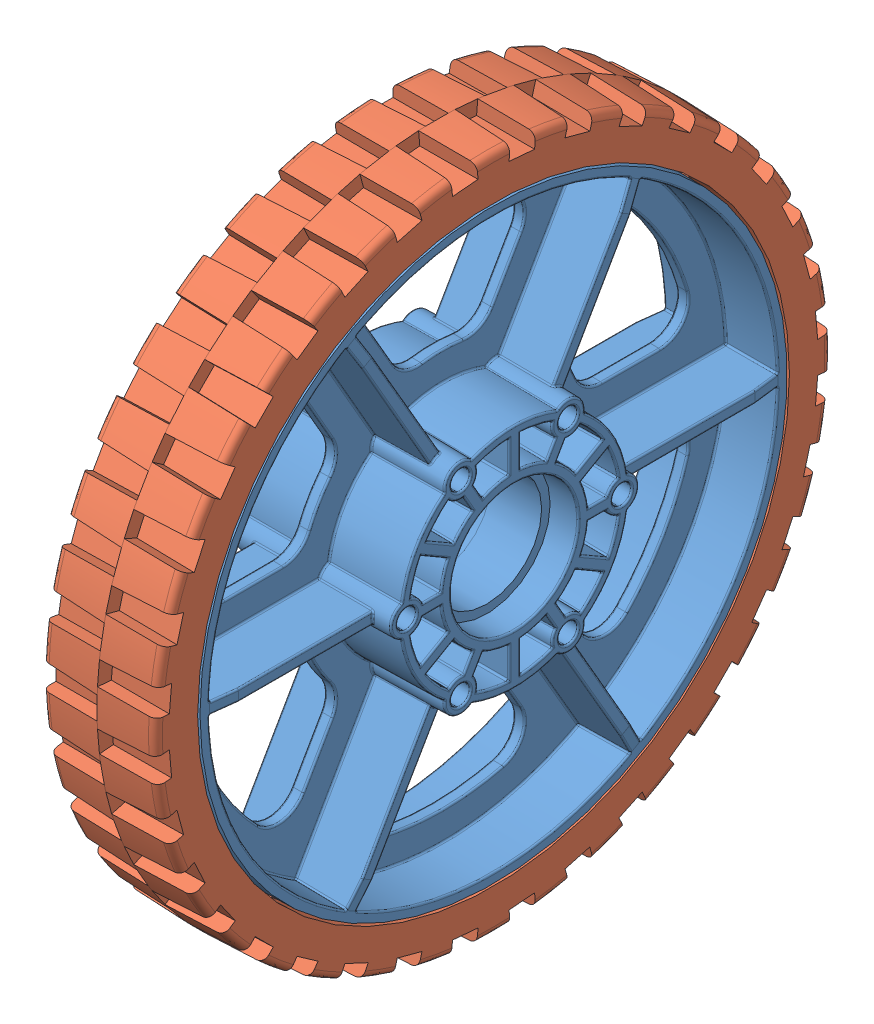
SolidWorks assembly AndyMark HiGrip 6in wheel, configuration Default. Lengths in mm.
Overall size (34.93 152.4 152.4).
2 component instances, 2 part files, 0 mates.
Components (placement in the parent):
- 6 wheel Rev 4-1: 6 wheel Rev 4 [Default] at (-52.6446 9.4231 21.378) size (34.93 132.08 132.08)
- 6 wheel tread II-1: 6 wheel tread II [Default] at (-65.3446 9.4231 21.378) x (0 0 -1) z (1 0 0) size (152.4 152.4 25.58)
